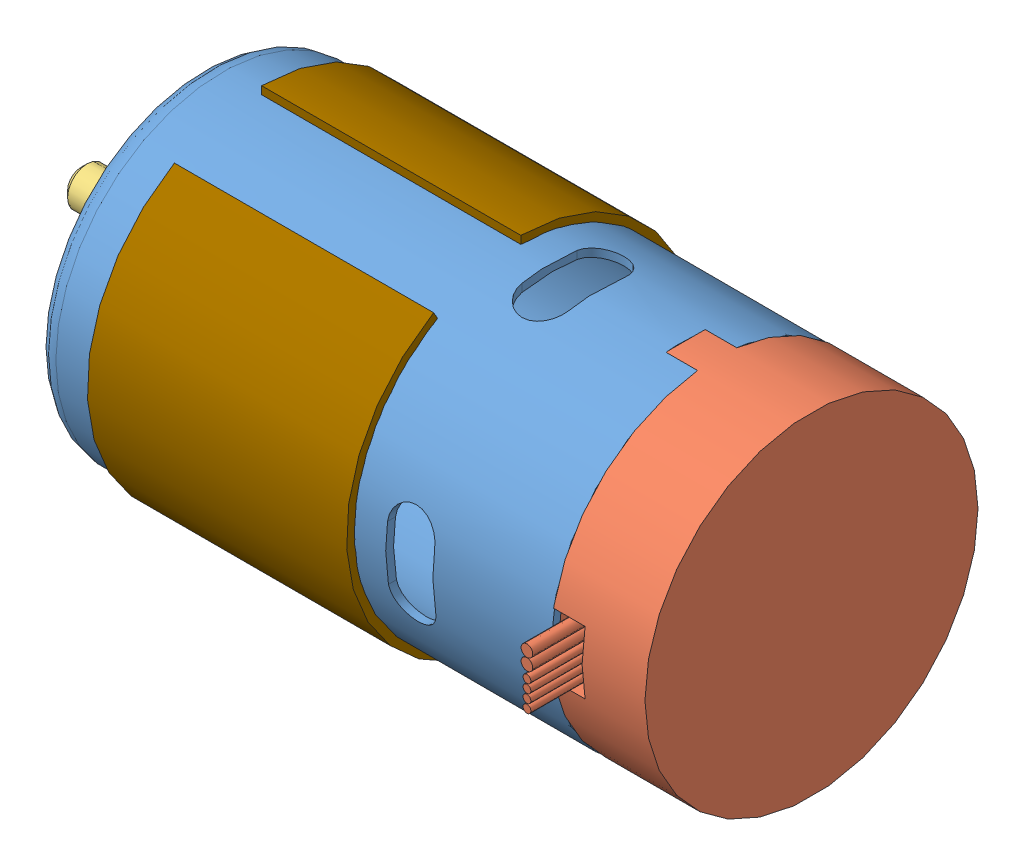
SolidWorks assembly IG42,PG420,MG49 DC Motor, configuration Default. Lengths in mm.
Overall size (663.68 60.65 131.7).
10 component instances, 9 part files, 10 mates.
Components (placement in the parent):
- Part1-1: Part1 [Default] at (142.3621 316.0202 439.7438) size (653.38 42.4 122.57)
- Part2-1: Part2 [Default] at (225.0621 316.0202 439.7438) x (0 1 0) z (0 0 1) size (42.4 20 47.4)
- Part3-1: Part3 [Default] at (147.0621 316.0202 439.7438) x (0 1 0) z (0 0 1) size (5 15 5)
- roulement_625-2z_2-1: roulement_625-2z_2 [Default] at (142.0621 316.0202 439.7438) size (5 16 16)
  - roulement_625-2z_2_01-1: roulement_625-2z_2_01 [Default] at origin size (5 16 16)
  - roulement_625-2z_2_02-1: roulement_625-2z_2_02 [Default] at origin size (5 8.4 8.4)
  - roulement_625-2z_2_03-1: roulement_625-2z_2_03 [Default] at origin size (0.55 13.71 13.71)
  - roulement_625-2z_2_04-1: roulement_625-2z_2_04 [Default] at origin size (0.55 13.71 13.71)
  - roulement_625-2z_2_05-1: roulement_625-2z_2_05 [Default] at origin size (2.38 12.58 12.58)
- Part4-1: Part4 [Default] at (155.0621 316.0202 439.7438) x (1 0 0) z (0 -0.5 0.866025) size (33 44.4 44.4)
Mates (geometry in assembly coordinates):
- Concentric1: concentric aligned: cylinder of Part1-1 through (142.3621 316.0202 439.7438) axis (-1 0 0) radius 8; cylinder of roulement_625-2z_2-1/roulement_625-2z_2_01-1 through (142.0621 316.0202 439.7438) axis (-1 0 0) radius 8
- Coincident1: coincident anti-aligned: plane of Part1-1 through (147.0621 324.0202 439.7438) normal (-1 0 0); plane of roulement_625-2z_2-1/roulement_625-2z_2_01-1 through (147.0621 322.6302 439.7438) normal (1 0 0)
- Concentric2: concentric anti-aligned: cylinder of Part3-1 through (132.0621 316.0202 439.7438) axis (1 0 0) radius 2.5; cylinder of roulement_625-2z_2-1/roulement_625-2z_2_02-1 through (142.0621 316.0202 439.7438) axis (-1 0 0) radius 2.5
- Coincident2: coincident aligned: plane of Part3-1 through (147.0621 316.0202 439.7438) normal (1 0 0); plane of roulement_625-2z_2-1/roulement_625-2z_2_02-1 through (147.0621 318.8202 439.7438) normal (1 0 0)
- Concentric3: concentric aligned: cylinder of Part1-1 through (142.3621 316.0202 439.7438) axis (-1 0 0) radius 20.2; cylinder of Part2-1 through (286.6217 316.0202 439.7438) axis (-1 0 0) radius 20.2
- Coincident3: coincident anti-aligned: plane of Part1-1 through (209.0621 327.2202 442.2438) normal (1 0 0); plane of Part2-1 through (209.0621 316.0202 439.7438) normal (-1 0 0)
- Coincident4: coincident anti-aligned: plane of Part1-1 through (213.0621 327.2202 442.2438) normal (0 0 -1); plane of Part2-1 through (213.0621 336.0649 442.2438) normal (0 0 1)
- Concentric4: concentric aligned: cylinder of Part1-1 through (142.3621 316.0202 439.7438) axis (-1 0 0) radius 21.2; cylinder of Part4-1 through (155.0621 316.0202 439.7438) axis (-1 0 0) radius 21.2
- Distance2: distance = 25 mm aligned: plane of Part4-1 through (188.0621 338.2202 439.7438) normal (1 0 0); plane of Part1-1 through (213.0621 337.2202 439.7438) normal (1 0 0)
- Parallel1: parallel anti-aligned: plane of Part1-1 through (213.0621 327.2202 442.2438) normal (0 0 -1); plane of Part4-1 through (155.0621 316.0202 439.7438) normal (0 0 1)
